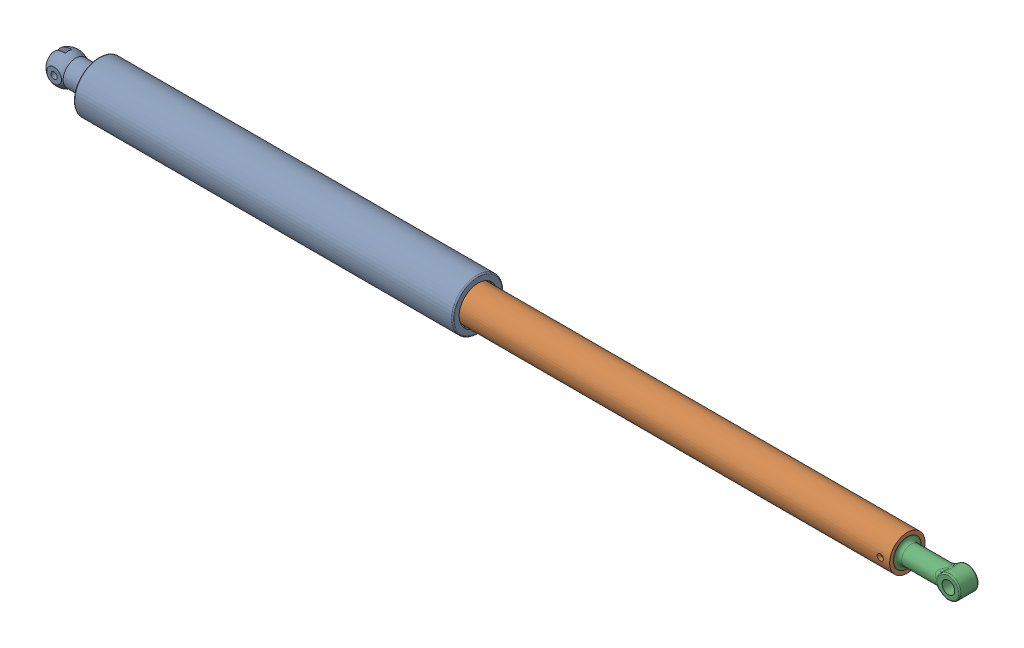
SolidWorks assembly LinearSpeedReducerAssembly, configuration Default. Lengths in mm.
Overall size (725.39 40 40).
3 component instances, 3 part files, 5 mates.
Components (placement in the parent):
- Linear speed reducer-1: Linear speed reducer [Default] at origin size (336.74 40 40)
- LinearSpeedReducerIn-1: LinearSpeedReducerIn [Default] at (239.6362 0 0) x (1 0 0) z (0 0 -1) size (400 34 34)
- LinearSpeedReducerConnection-1: LinearSpeedReducerConnection [Default] at (624.6362 0 0) x (0 0 1) z (0 1 0) size (22 64.01 22)
Mates (geometry in assembly coordinates):
- Concentric1: concentric anti-aligned: cylinder of LinearSpeedReducerIn-1 through (632.1362 -17 0) axis (0 1 0) radius 2.5; cylinder of LinearSpeedReducerConnection-1 through (632.1362 11 0) axis (0 -1 0) radius 2.5
- Concentric2: concentric aligned: cylinder of LinearSpeedReducerIn-1 through (239.6362 0 0) axis (-1 0 0) radius 11; cylinder of LinearSpeedReducerConnection-1 through (639.6362 0 0) axis (-1 0 0) radius 11
- Concentric3: concentric aligned: cylinder of Linear speed reducer-1 through (0 0 0) axis (-1 0 0) radius 17; cylinder of LinearSpeedReducerIn-1 through (239.6362 0 0) axis (-1 0 0) radius 17
- LimitDistance1: limit distance = 236.6362 mm anti-aligned: plane of LinearSpeedReducerIn-1 through (239.6362 0 0) normal (-1 0 0); plane of Linear speed reducer-1 through (3 0 0) normal (1 0 0)
- Perpendicular1: perpendicular: plane of LinearSpeedReducerConnection-1 through (679.6362 0 7.5) normal (0 0 1)
